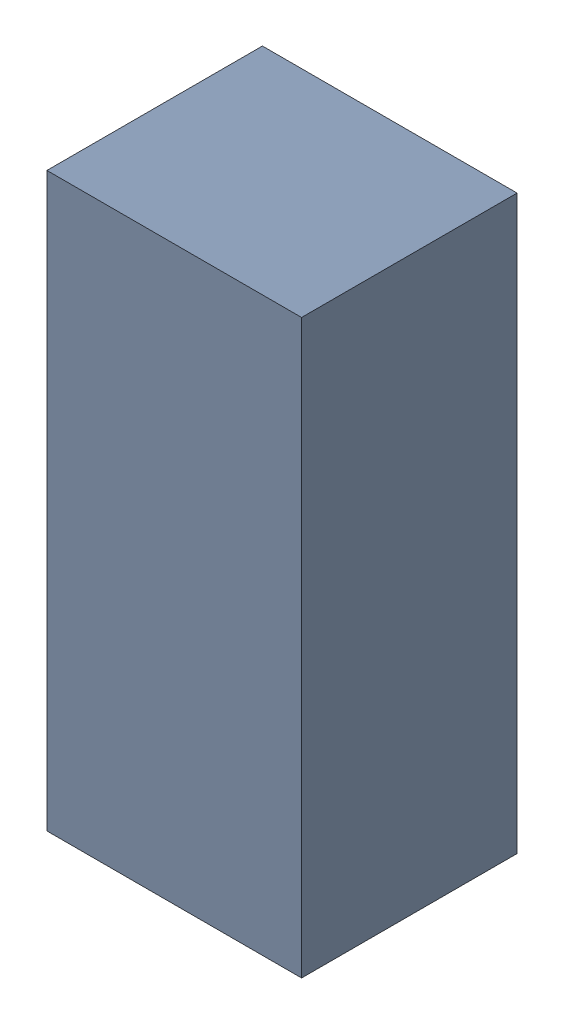
SolidWorks assembly D3, configuration Default. Lengths in mm.
Overall size (1.3 2.92 1.1).
2 component instances, 1 part files, 0 mates.
Components (placement in the parent):
- 6151663024-1: 6151663024 [Default] at (15.367 1.143 0.01) size (1.3 2.92 1.1)
  - Extruded-1: Extruded [Default] at origin size (1.3 2.92 1.1)
